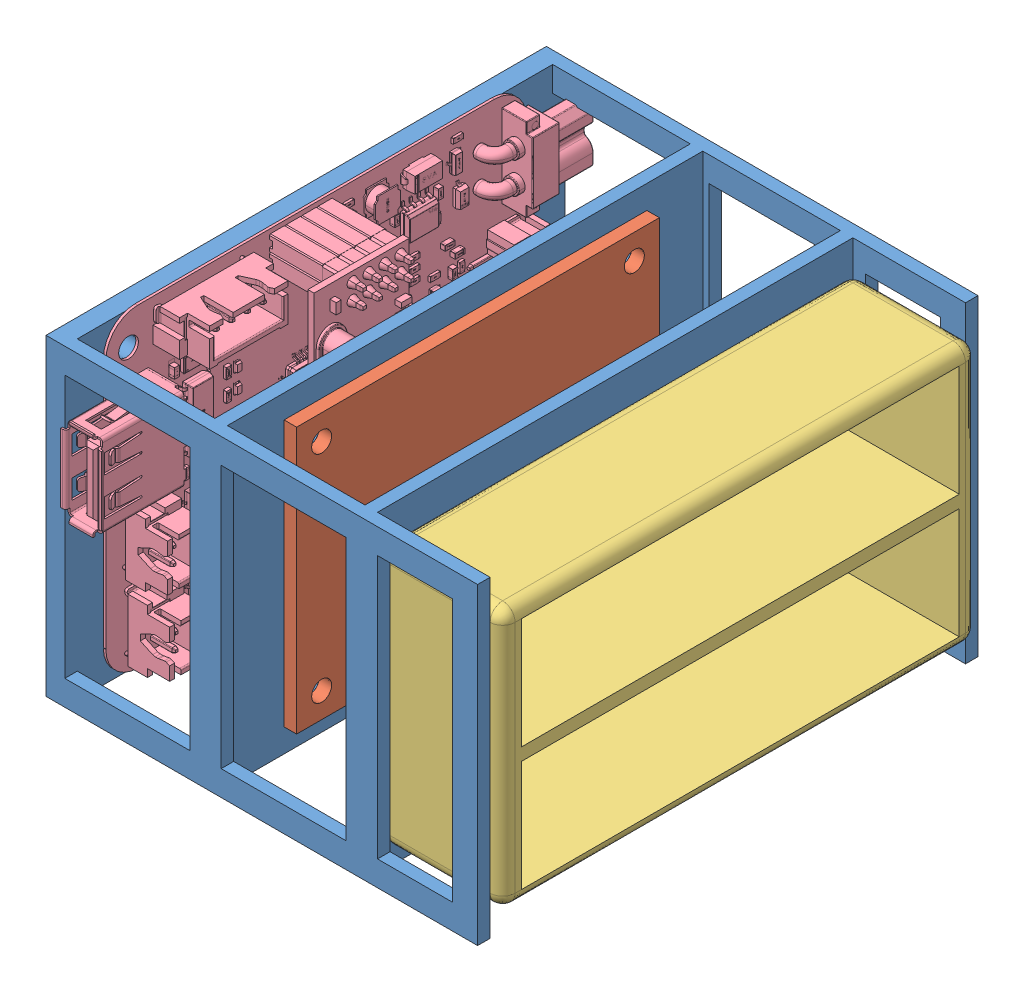
SolidWorks assembly 电路部分, configuration 默认. Lengths in mm.
Overall size (71.89 50.25 81.37).
4 component instances, 4 part files, 10 mates.
Components (placement in the parent):
- 支架-1: 支架 [默认] at origin size (69 50 80)
- 24路舵机控制板-1: 24路舵机控制板 [默认] at (27 46.25 -69.0655) x (0 0 1) z (0 1 0) size (58 22 42.5)
- 电池盒-1: 电池盒 [默认] at (51 25 -40) x (0 -1 0) z (0 0 1) size (41.5 20 76)
- 中控-1: 中控 [默认] at (3.4115 0.127 -6.282) x (0 0 -1) z (1 0 0) size (81.06 50.25 19.75)
Mates (geometry in assembly coordinates):
- 重合3: coincident anti-aligned: plane of 支架-1 through (3 50 -78) normal (0 0 1); plane of 电池盒-1 through (71 45.75 -78) normal (0 0 -1)
- 重合4: coincident anti-aligned: plane of 支架-1 through (3 50 -2) normal (0 0 -1); plane of 电池盒-1 through (71 45.75 -2) normal (0 0 1)
- 重合8: coincident anti-aligned: plane of 支架-1 through (27 50 -78) normal (1 0 0); plane of 24路舵机控制板-1 through (27 46.25 -69.0655) normal (-1 0 0)
- 重合9: coincident aligned: plane of 支架-1 through (0 0 0) normal (0 -1 0); plane of 中控-1 through (3 0 -68.258) normal (0 -1 0)
- 重合10: coincident anti-aligned: plane of 支架-1 through (3 50 -78) normal (1 0 0); plane of 中控-1 through (3 0 -11.282) normal (-1 0 0)
- 距离1: distance = 4.25 mm aligned: plane of 电池盒-1 through (71 45.75 -2) normal (0 1 0); plane of 支架-1 through (0 50 0) normal (0 1 0)
- 重合12: coincident anti-aligned: plane of 支架-1 through (51 50 -78) normal (1 0 0); plane of 电池盒-1 through (51 25 -40) normal (-1 0 0)
- 距离2: distance = 3.75 mm aligned: plane of 24路舵机控制板-1 through (29 46.25 -69.0655) normal (0 1 0); plane of 支架-1 through (0 50 0) normal (0 1 0)
- 平行2: parallel aligned: cylinder of 支架-1 through (17 7.75 -15.0463) axis (1 0 0) radius 1.6; cylinder of 24路舵机控制板-1 through (27 7.75 -15.0655) axis (1 0 0) radius 1.6
- 距离3: distance = 10.9345 mm aligned: plane of 24路舵机控制板-1 through (29 46.25 -69.0655) normal (0 0 -1); plane of 支架-1 through (0 50 -80) normal (0 0 -1)
